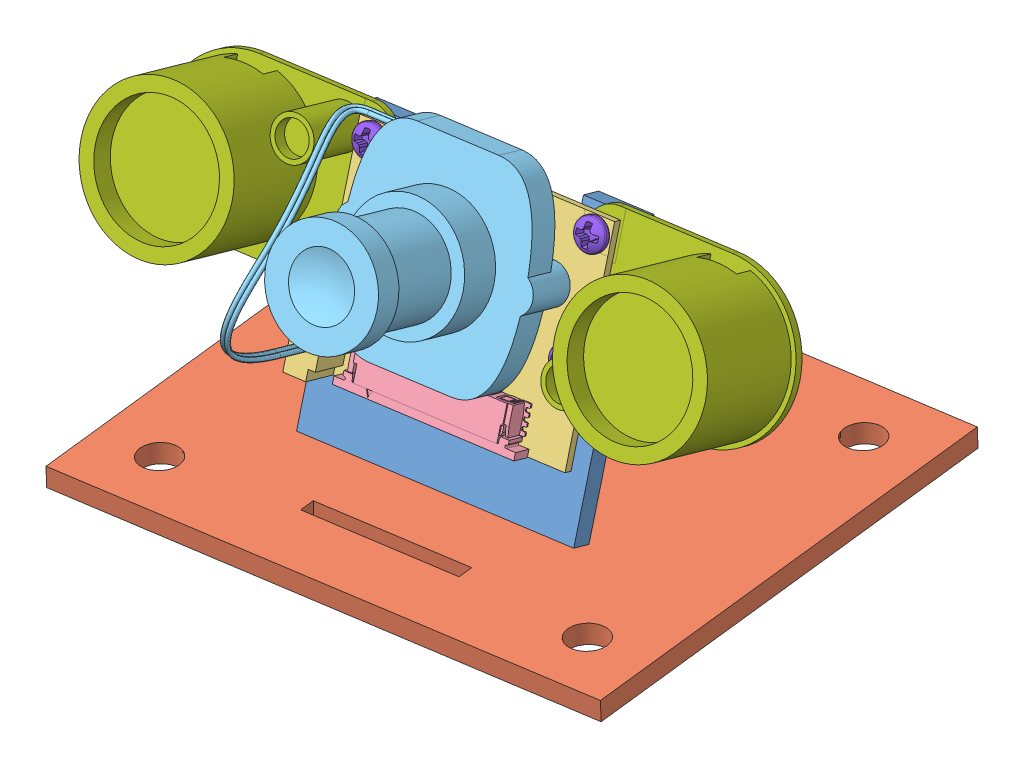
SolidWorks assembly Camera, configuration Default. Lengths in mm.
Overall size (84.39 52.08 73.09).
19 component instances, 9 part files, 5 mates.
Components (placement in the parent):
- Camera Mount A-1: Camera Mount A [Default] at (118.6839 468.96 105.3754) x (-0.992812 -0.033694 0.114845) z (0.070181 -0.941166 0.330576) size (35 14.23 35)
- Camera Mount B-1: Camera Mount B [Default] at (120.8715 464.9976 123.1238) x (0.992812 0.033694 -0.114845) z (0.114845 0.001942 0.993382) size (70 13.62 60)
- JES Camera Module Kit Embedded IR-CUT Night Vision-1: JES Camera Module Kit Embedded IR-CUT Night Vision [Default] at (116.973 493.5407 97.7965) x (0.992812 0.033694 -0.114845) z (0.070181 -0.941166 0.330576) size (80 28.97 30.78)
  - Raspberry Pi Camera-1: Raspberry Pi Camera [Default] at origin size (32.15 27.14 30.78)
    - camera pcb-1: camera pcb [Default] at origin size (32.15 5.6 26.65)
    - TE-1-84952-5-1: TE-1-84952-5 [Default] at (0 2.315 16.92) size (22.92 2.56 6.54)
    - camera lens-1: camera lens [Default] at (0 1 0) size (27.15 24.9 27.93)
    - 92005A002_METRIC PAN HEAD PHILLIPS MACHINE SCREW-1: 92005A002_METRIC PAN HEAD PHILLIPS MACHINE SCREW [92005A002] at (10 3 0) x (1 0 0) z (0 -1 0) size (3.2 3.2 4.3)
    - 92005A002_METRIC PAN HEAD PHILLIPS MACHINE SCREW-2: 92005A002_METRIC PAN HEAD PHILLIPS MACHINE SCREW [92005A002] at (-10 3 0) x (0.982082 0 -0.188455) z (0 -1 0) size (3.2 3.2 4.3)
  - Raspberry PI IR illuminator-1: Raspberry PI IR illuminator [Default] at (-29.88 -1 0.05) x (0 0 -1) z (1 0 0) size (20.24 14.94 27.86)
  - Raspberry PI IR illuminator-2: Raspberry PI IR illuminator [Default] at (29.88 -1 0.05) x (0 0 1) z (-1 0 0) size (20.24 14.94 27.86)
  - 92005A016_METRIC PAN HEAD PHILLIPS MACHINE SCREW-1: 92005A016_METRIC PAN HEAD PHILLIPS MACHINE SCREW [92005A016] at (14 -3 -6.7) x (1 0 0) z (0 1 0) size (4 4 5.58)
  - 90591A265_ZINC PLATED STEEL HEX NUT-1: 90591A265_ZINC PLATED STEEL HEX NUT [90591A265] at (14 -1.8 -6.7) x (1 0 0) z (0 1 0) size (4 4.62 1.83)
  - 90591A265_ZINC PLATED STEEL HEX NUT-2: 90591A265_ZINC PLATED STEEL HEX NUT [90591A265] at (14 -1.8 6.8) x (1 0 0) z (0 1 0) size (4 4.62 1.83)
  - 90591A265_ZINC PLATED STEEL HEX NUT-3: 90591A265_ZINC PLATED STEEL HEX NUT [90591A265] at (-14 -1.8 -6.7) x (1 0 0) z (0 1 0) size (4 4.62 1.83)
  - 90591A265_ZINC PLATED STEEL HEX NUT-4: 90591A265_ZINC PLATED STEEL HEX NUT [90591A265] at (-14 -1.8 6.8) x (1 0 0) z (0 1 0) size (4 4.62 1.83)
  - 92005A016_METRIC PAN HEAD PHILLIPS MACHINE SCREW-2: 92005A016_METRIC PAN HEAD PHILLIPS MACHINE SCREW [92005A016] at (14 -3 6.8) x (1 0 0) z (0 1 0) size (4 4 5.58)
  - 92005A016_METRIC PAN HEAD PHILLIPS MACHINE SCREW-3: 92005A016_METRIC PAN HEAD PHILLIPS MACHINE SCREW [92005A016] at (-14 -3 -6.7) x (1 0 0) z (0 1 0) size (4 4 5.58)
  - 92005A016_METRIC PAN HEAD PHILLIPS MACHINE SCREW-4: 92005A016_METRIC PAN HEAD PHILLIPS MACHINE SCREW [92005A016] at (-14 -3 6.8) x (1 0 0) z (0 1 0) size (4 4 5.58)
Mates (geometry in assembly coordinates):
- Coincident76: coincident anti-aligned: plane of Camera Mount A-1 through (123.4122 469.1205 104.8284) normal (0.992812 0.033694 -0.114845); plane of Camera Mount B-1 through (120.7021 482.6153 85.3591) normal (-0.992812 -0.033694 0.114845)
- Concentric9: concentric aligned: circle of Camera Mount A-1; circle of JES Camera Module Kit Embedded IR-CUT Night Vision-1/90591A265_ZINC PLATED STEEL HEX NUT-1
- Concentric10: concentric aligned: circle of Camera Mount A-1; circle of JES Camera Module Kit Embedded IR-CUT Night Vision-1/90591A265_ZINC PLATED STEEL HEX NUT-3
- Coincident80: coincident anti-aligned: plane of Camera Mount A-1 through (118.6839 468.96 105.3754) normal (0.09695 0.33626 0.936766); plane of JES Camera Module Kit Embedded IR-CUT Night Vision-1/Raspberry PI IR illuminator-2 through (146.5448 494.1642 93.4447) normal (-0.09695 -0.33626 -0.936766)
- Coincident81: coincident aligned: cylinder of Camera Mount A-1; cylinder of Camera Mount B-1 through (125.0743 472.9438 92.673) axis (0.992812 0.033694 -0.114845) radius 2.5
